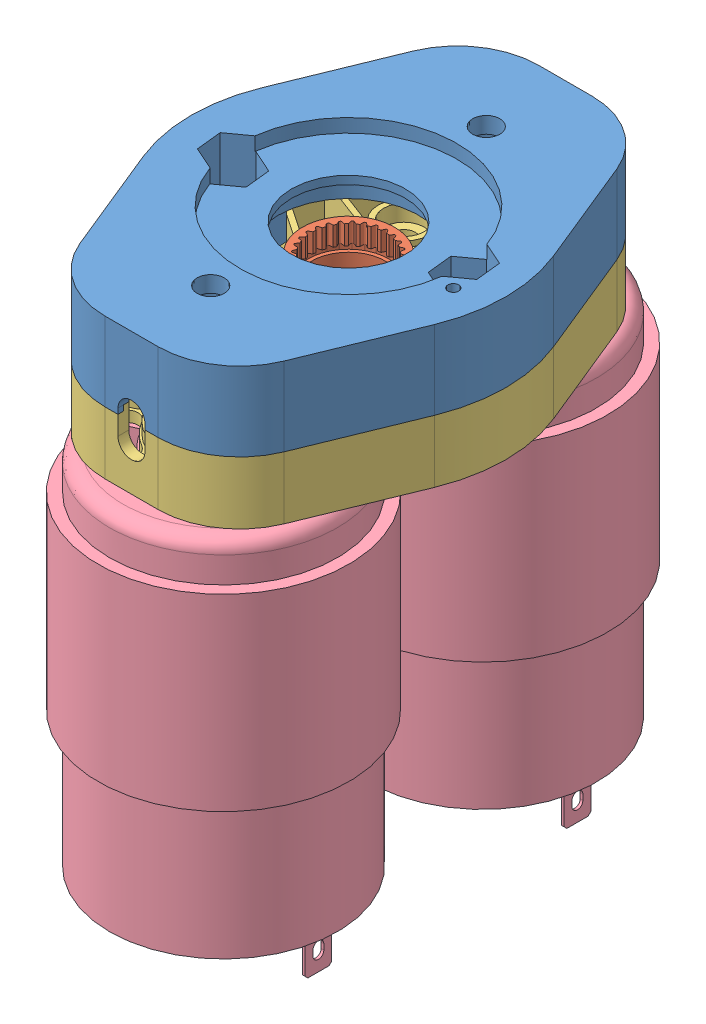
SolidWorks assembly Dual_Motor_Input_with_775_Series, configuration Default. Lengths in mm.
Overall size (58 101.2 93.95).
5 component instances, 4 part files, 0 mates.
Components (placement in the parent):
- 217-3141-001 Rev1-1: 217-3141-001 Rev1 [Default] at (-8.7431 -33.263 42.5163) x (0 0 1) z (-1 0 0) size (80 14.5 58)
- 217-3141-007 Rev1_30T 32DP-1: 217-3141-007 Rev1_30T 32DP [Default] at (-8.7431 -45.3229 42.5163) x (0 -1 0) z (-0.999183 0 0.040426) size (22.38 25.55 25.47)
- 217-3141-004 Rev1-1: 217-3141-004 Rev1 [Default] at (-8.7431 -46.2629 42.5163) x (0 0 1) z (0 1 0) size (80 58 12.5)
- BB RS775-18V-1: BB RS775-18V [Default] at (-7.9094 -52.5129 66.3905) x (0 -1 0) z (0 0 1) size (88 46.2 46.2)
- BB RS775-18V-2: BB RS775-18V [Default] at (-7.9094 -52.5129 18.6422) x (0 -1 0) z (0 0 -1) size (88 46.2 46.2)
